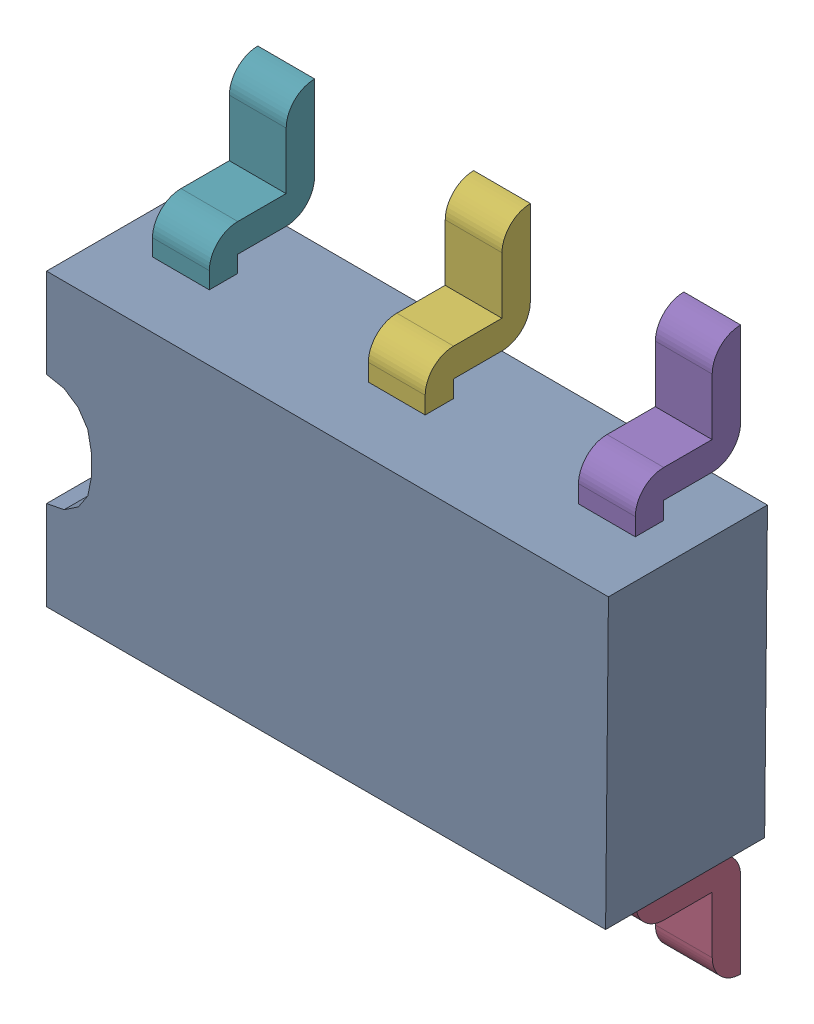
SolidWorks assembly U4, configuration Défaut. Lengths in mm.
Overall size (2.51 2.51 0.76).
8 component instances, 7 part files, 0 mates.
Components (placement in the parent):
- Open CASCADE STEP translator 6.8 1.31.1-1: Open CASCADE STEP translator 6.8 1.31.1 [Défaut] at origin size (2.51 2.51 0.76)
  - Body_1_15-1: Body_1_15 [Défaut] at origin size (2.51 1.3 0.71)
  - Pin_1_11-1: Pin_1_11 [Défaut] at (-2.1844 -0.254 0) x (0 1 0) z (0 0 1) size (0.63 0.25 0.47)
  - Pin_2_11-1: Pin_2_11 [Défaut] at (-1.2446 -1.1938 0) x (0 1 0) z (0 0 1) size (0.63 0.25 0.47)
  - Pin_3_7-1: Pin_3_7 [Défaut] at (-0.2794 -2.159 0) x (0 1 0) z (0 0 1) size (0.63 0.25 0.47)
  - Pin_4_5-1: Pin_4_5 [Défaut] at (-0.2267 2.1106 0) x (-0.002065 -0.999998 0) z (0 0 1) size (0.59 0.25 0.47)
  - Pin_5_4-1: Pin_5_4 [Défaut] at (-1.1684 1.1708 0) x (-0.002073 -0.999998 0) z (0 0 1) size (0.58 0.25 0.47)
  - Pin_6_4-1: Pin_6_4 [Défaut] at (-2.1356 0.2056 0) x (-0.002061 -0.999998 0) z (0 0 1) size (0.58 0.25 0.47)
